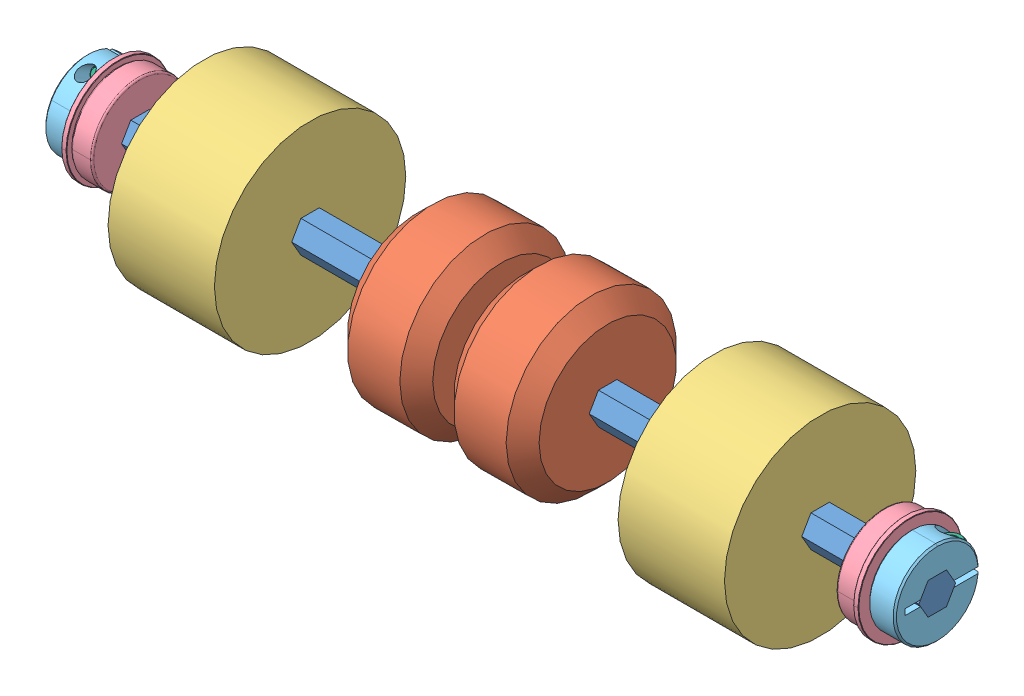
SolidWorks assembly Flywheel Shaft, configuration Default. Lengths in mm.
Overall size (254.96 57.15 57.15).
14 component instances, 6 part files, 21 mates.
Components (placement in the parent):
- Hex Shaft-1: Hex Shaft [Default] at origin size (254 9.53 11)
- FlyWheel-1: FlyWheel [Default] at origin size (57.15 50.8 50.8)
- Brass Wheel-1: Brass Wheel [Default] at (-92.0217 0 0) size (31.75 57.15 57.15)
- Brass Wheel-2: Brass Wheel [Default] at (60.2717 0 0) size (31.75 57.15 57.15)
- Flanged Bearing.step-1: Flanged Bearing.step [Default] at (111.0717 0 0) x (0 0 -1) z (1 0 0) size (31.12 31.12 7.93)
- Flanged Bearing.step-2: Flanged Bearing.step [Default] at (-111.0717 0 0) x (0 0 1) z (-1 0 0) size (31.12 31.12 7.93)
- Shaft Collar-2: Shaft Collar [Default] at (127 0 0) x (0 0 -1) z (0 1 0) size (25.37 8.96 25.4)
  - Shaft Collar.STEP-1: Shaft Collar.STEP [Default] at origin size (25.37 8.96 25.4)
    - am-2300 Clamp Only.STEP-1: am-2300 Clamp Only.STEP [Default] at origin size (25.37 8 25.4)
    - am-2300 Screw Only_91251A192.STEP-1: am-2300 Screw Only_91251A192.STEP [Default] at (7.9698 4.0005 -5.969) x (-0.923728 -0.383049 0) z (0 0 -1) size (6.86 6.86 13.69)
- Shaft Collar-3: Shaft Collar [Default] at (-127 0 0) x (0 0.866025 -0.5) z (0 -0.5 -0.866025) size (25.37 8.96 25.4)
  - Shaft Collar.STEP-1: Shaft Collar.STEP [Default] at origin size (25.37 8.96 25.4)
    - am-2300 Clamp Only.STEP-1: am-2300 Clamp Only.STEP [Default] at origin size (25.37 8 25.4)
    - am-2300 Screw Only_91251A192.STEP-1: am-2300 Screw Only_91251A192.STEP [Default] at (7.9698 4.0005 -5.969) x (-0.923728 -0.383049 0) z (0 0 -1) size (6.86 6.86 13.69)
Mates (geometry in assembly coordinates):
- Coincident1: coincident anti-aligned: plane of Hex Shaft-1 through (127 -4.7625 2.7496) normal (0 -1 0); plane of FlyWheel-1 through (-28.575 -4.7625 2.7496) normal (0 1 0)
- Coincident2: coincident anti-aligned: plane of Hex Shaft-1 through (127 4.7625 2.7496) normal (0 0.5 0.866025); plane of FlyWheel-1 through (-28.575 4.7625 2.7496) normal (0 -0.5 -0.866025)
- Distance1: distance = 123.825 mm anti-aligned: plane of FlyWheel-1 through (-3.175 0 0) normal (1 0 0); plane of Hex Shaft-1 through (-127 0 0) normal (-1 0 0)
- Coincident9: coincident: plane of Hex Shaft-1 through (127 0 -5.4993) normal (0 0.5 -0.866025); plane of Brass Wheel-1 through (-103.1093 0 -5.4993) normal (0 -0.5 0.866025)
- Coincident10: coincident: plane of Hex Shaft-1 through (127 4.7625 2.7496) normal (0 0.5 0.866025); plane of Brass Wheel-1 through (-103.1093 4.7625 2.7496) normal (0 -0.5 -0.866025)
- Coincident11: coincident: plane of Hex Shaft-1 through (127 -4.7625 2.7496) normal (0 -1 0); plane of Brass Wheel-2 through (60.7446 -4.7625 2.7496) normal (0 1 0)
- Coincident12: coincident: plane of Hex Shaft-1 through (127 0 -5.4993) normal (0 0.5 -0.866025); plane of Brass Wheel-2 through (60.7446 0 -5.4993) normal (0 -0.5 0.866025)
- Coincident14: coincident: plane of Hex Shaft-1 through (127 0 5.4993) normal (0 -0.5 0.866025); plane of Flanged Bearing.step-1 through (118.999 0 5.4993) normal (0 0.5 -0.866025)
- Coincident15: coincident: plane of Hex Shaft-1 through (127 4.7625 2.7496) normal (0 0.5 0.866025); plane of Flanged Bearing.step-1 through (118.999 4.7625 2.7496) normal (0 -0.5 -0.866025)
- Coincident16: coincident: plane of Hex Shaft-1 through (127 -4.7625 -2.7496) normal (0 -0.5 -0.866025); plane of Flanged Bearing.step-2 through (-114.5804 0 -5.4993) normal (0 0.5 0.866025)
- Coincident17: coincident: plane of Hex Shaft-1 through (127 0 -5.4993) normal (0 0.5 -0.866025); plane of Flanged Bearing.step-2 through (-114.5804 4.7625 -2.7496) normal (0 -0.5 0.866025)
- Coincident21: coincident anti-aligned: plane of Hex Shaft-1 through (127 0 5.4993) normal (0 -0.5 0.866025); plane of Shaft Collar-3/Shaft Collar.STEP-1/am-2300 Clamp Only.STEP-1 through (-118.999 0 5.4993) normal (0 0.5 -0.866025)
- Coincident22: coincident aligned: plane of Hex Shaft-1 through (-127 0 0) normal (-1 0 0); plane of Shaft Collar-3/Shaft Collar.STEP-1/am-2300 Clamp Only.STEP-1 through (-127 0 0) normal (-1 0 0)
- Coincident23: coincident anti-aligned: plane of Hex Shaft-1 through (127 -4.7625 -2.7496) normal (0 -0.5 -0.866025); plane of Shaft Collar-3/Shaft Collar.STEP-1/am-2300 Clamp Only.STEP-1 through (-118.999 -4.7625 -2.7496) normal (0 0.5 0.866025)
- Coincident32: coincident: plane of Hex Shaft-1 through (127 -4.7625 2.7496) normal (0 -1 0); plane of Shaft Collar-2/Shaft Collar.STEP-1/am-2300 Clamp Only.STEP-1 through (118.999 -4.7625 -2.7496) normal (0 1 0)
- Coincident33: coincident: plane of Hex Shaft-1 through (127 4.7625 2.7496) normal (0 0.5 0.866025); plane of Shaft Collar-2/Shaft Collar.STEP-1/am-2300 Clamp Only.STEP-1 through (118.999 0 5.4993) normal (0 -0.5 -0.866025)
- Coincident34: coincident aligned: plane of Hex Shaft-1 through (127 0 0) normal (1 0 0); plane of Shaft Collar-2/Shaft Collar.STEP-1/am-2300 Clamp Only.STEP-1 through (127 0 0) normal (1 0 0)
- Coincident35: coincident anti-aligned: plane of Flanged Bearing.step-1 through (118.999 0 0) normal (1 0 0); plane of Shaft Collar-2/Shaft Collar.STEP-1/am-2300 Clamp Only.STEP-1 through (118.999 0 0) normal (-1 0 0)
- Coincident36: coincident anti-aligned: plane of Flanged Bearing.step-2 through (-118.999 0 0) normal (-1 0 0); plane of Shaft Collar-3/Shaft Collar.STEP-1/am-2300 Clamp Only.STEP-1 through (-118.999 0 0) normal (1 0 0)
- Distance2: distance = 19.05 mm anti-aligned: plane of Brass Wheel-2 through (92.0217 0 0) normal (1 0 0); plane of Flanged Bearing.step-1 through (111.0717 0 0) normal (-1 0 0)
- Distance3: distance = 19.05 mm anti-aligned: plane of Brass Wheel-1 through (-92.0217 0 0) normal (-1 0 0); plane of Flanged Bearing.step-2 through (-111.0717 0 0) normal (1 0 0)
